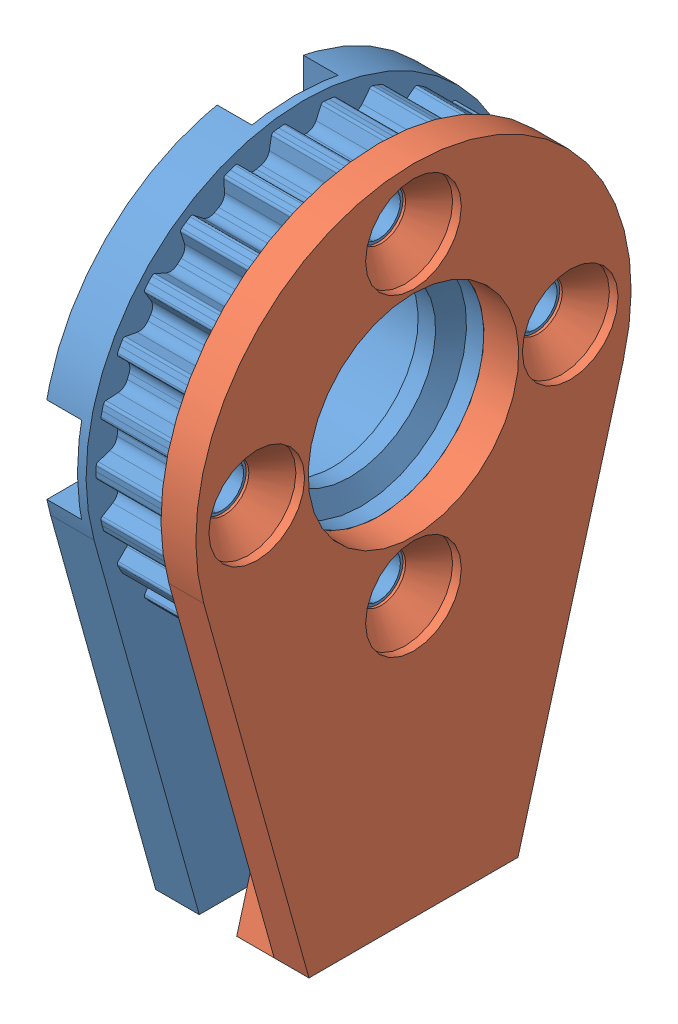
SolidWorks assembly lower limb assembly, configuration Default. Lengths in mm.
Overall size (8.8 37.5 25).
2 component instances, 2 part files, 6 mates.
Components (placement in the parent):
- 26t-s3m-pulley-ankle-1: 26t-s3m-pulley-ankle [Default] x (1 0 0) z (0 1 0) size (6.8 25 37.5)
- lower arm upper cover-1: lower arm upper cover [Default] at (3.65 0 0) x (0 0 1) z (0 -1 0) size (25 4.15 37.5)
Mates (geometry in assembly coordinates):
- Coincident1: coincident anti-aligned: plane of 26t-s3m-pulley-ankle-1 through (0 0 0) normal (0 0 -1)
- Coincident3: coincident aligned: plane of 26t-s3m-pulley-ankle-1 through (0 0 0) normal (1 0 0)
- Coincident4: coincident aligned: plane of 26t-s3m-pulley-ankle-1 through (0 0 0) normal (0 1 0)
- Concentric1: concentric aligned: cylinder of 26t-s3m-pulley-ankle-1 through (-2.15 0 0) axis (1 0 0) radius 6.05; cylinder of lower arm upper cover-1 through (2.15 0 0) axis (1 0 0) radius 12.5
- Coincident5: coincident anti-aligned: plane of 26t-s3m-pulley-ankle-1 through (2.15 0 -9) normal (1 0 0); plane of lower arm upper cover-1 through (2.15 0 0) normal (-1 0 0)
- Concentric2: concentric anti-aligned: cylinder of 26t-s3m-pulley-ankle-1 through (2.15 9 0) axis (-1 0 0) radius 1.25; cylinder of lower arm upper cover-1 through (3.65 9 0) axis (1 0 0) radius 1.4
